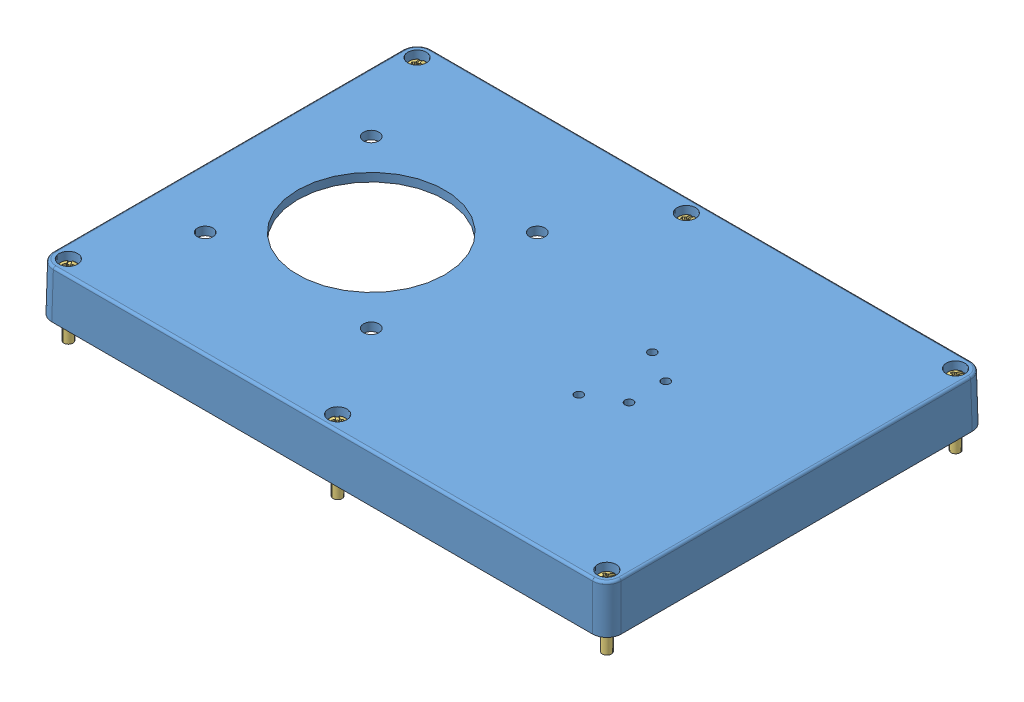
SolidWorks assembly enclosure-top, configuration Default. Lengths in mm.
Overall size (240 29.83 160).
8 component instances, 3 part files, 0 mates.
Components (placement in the parent):
- 1554VA-VB Lid-1: 1554VA-VB Lid [Default] x (1 0 0) z (0 -1 0) size (240 160 21.56)
- 1554VA-VB GASKET-1: 1554VA-VB GASKET [Default] x (1 0 0) z (0 -1 0) size (237.5 157.5 1.8)
- SC583 (screw M4-0.7X 25mm PN)-1: SC583 (screw M4-0.7X 25mm PN) [Default] at (113.5 15 73.5) x (-0.268218 0 0.963358) z (-0.963358 0 -0.268218) size (6.9 27.56 6.9)
- SC583 (screw M4-0.7X 25mm PN)-7: SC583 (screw M4-0.7X 25mm PN) [Default] at (113.5 15 -73.5) x (-0.081863 0 0.996644) z (-0.996644 0 -0.081863) size (6.9 27.56 6.9)
- SC583 (screw M4-0.7X 25mm PN)-8: SC583 (screw M4-0.7X 25mm PN) [Default] at (0 15 -73.5) x (0.134912 0 0.990858) z (-0.990858 0 0.134912) size (6.9 27.56 6.9)
- SC583 (screw M4-0.7X 25mm PN)-9: SC583 (screw M4-0.7X 25mm PN) [Default] at (-113.5 15 -73.5) x (0.36344 0 0.931618) z (-0.931618 0 0.36344) size (6.9 27.56 6.9)
- SC583 (screw M4-0.7X 25mm PN)-10: SC583 (screw M4-0.7X 25mm PN) [Default] at (-113.5 15 73.5) x (0.575391 0 0.817879) z (-0.817879 0 0.575391) size (6.9 27.56 6.9)
- SC583 (screw M4-0.7X 25mm PN)-11: SC583 (screw M4-0.7X 25mm PN) [Default] at (0 15 73.5) x (0.744382 0 0.667754) z (-0.667754 0 0.744382) size (6.9 27.56 6.9)
